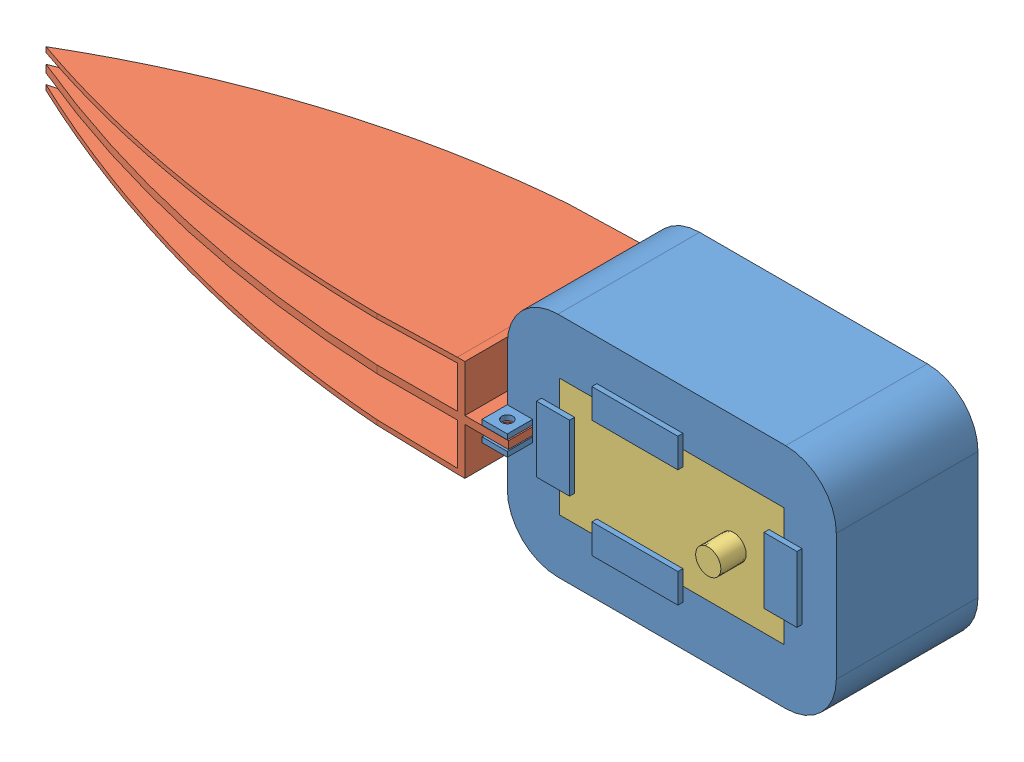
SolidWorks assembly link6, configuration 預設. Lengths in mm.
Overall size (170.1 45 38.21).
3 component instances, 3 part files, 6 mates.
Components (placement in the parent):
- bus2_tail-2: bus2_tail [預設] at (-9.0934 -16.9047 37.067) size (65 45 38)
- bus_final_tail-2: bus_final_tail [預設] at (-73.1187 -16.9047 50.3365) x (-1 0 0.00071) z (0 1 0) size (110.1 38.13 25.31)
- bus_servo-4: bus_servo [預設] at (-16.5803 -28.3978 37.067) x (1 0 0) z (0 -1 0) size (44.4 38 23.4)
Mates (geometry in assembly coordinates):
- 重合/共線/共點11: coincident anti-aligned: plane of bus2_tail-2 through (-58.728 -28.6047 76.067) normal (0 1 0); plane of bus_servo-4 through (-58.728 -28.6047 65.067) normal (0 -1 0)
- 重合/共線/共點12: coincident anti-aligned: plane of bus2_tail-2 through (-14.328 -5.2047 76.067) normal (-1 0 0); plane of bus_servo-4 through (-14.328 -5.2047 65.067) normal (1 0 0)
- 重合/共線/共點13: coincident aligned: plane of bus2_tail-2 through (-9.0934 -16.9047 65.067) normal (0 0 1); plane of bus_servo-4 through (-16.5803 -28.3978 65.067) normal (0 0 1)
- 同軸心6: concentric anti-aligned: cylinder of bus2_tail-2 through (-66.528 -11.9047 67.567) axis (0 -1 0) radius 1.1; cylinder of bus_final_tail-2 through (-66.528 -17.6547 67.567) axis (0 1 0) radius 1.1
- 同軸心7: concentric anti-aligned: cylinder of bus2_tail-2 through (-66.528 -11.9047 34.567) axis (0 -1 0) radius 1.1; cylinder of bus_final_tail-2 through (-66.528 -17.6547 34.567) axis (0 1 0) radius 1.1
- 平行相距7: distance = 0.25 mm anti-aligned: plane of bus_final_tail-2 through (-73.1187 -17.6547 50.3365) normal (0 -1 0); plane of bus2_tail-2 through (-9.0934 -17.9047 37.067) normal (0 1 0)
